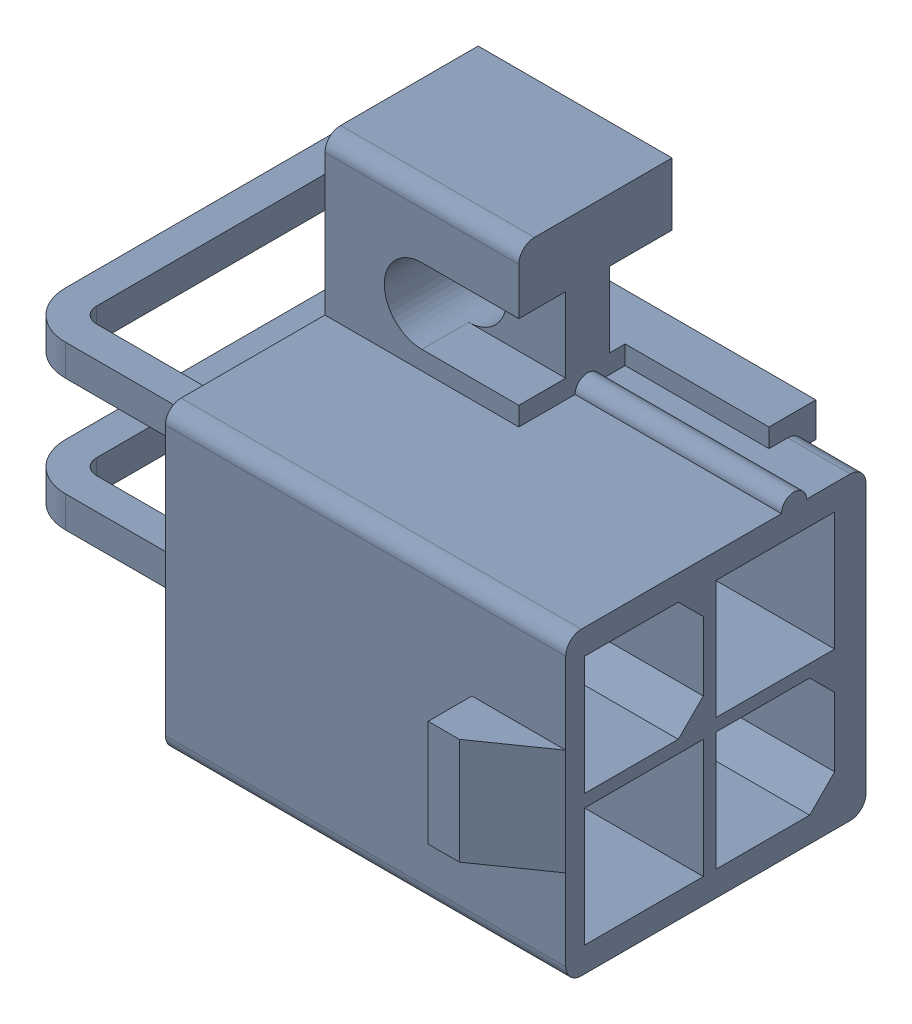
SolidWorks assembly Power_Input1, configuration Default. Lengths in mm.
Overall size (19.9 19.6 14.9).
2 component instances, 1 part files, 0 mates.
Components (placement in the parent):
- 039291047-1: 039291047 [Default] at (184.111 17.272 0) x (0 1 0) z (1 0 0) size (19.6 14.9 19.9)
  - Open CASCADE STEP translator 6.2 1.18.1.1-1: Open CASCADE STEP translator 6.2 1.18.1.1 [Default] at origin size (19.6 14.9 19.9)
